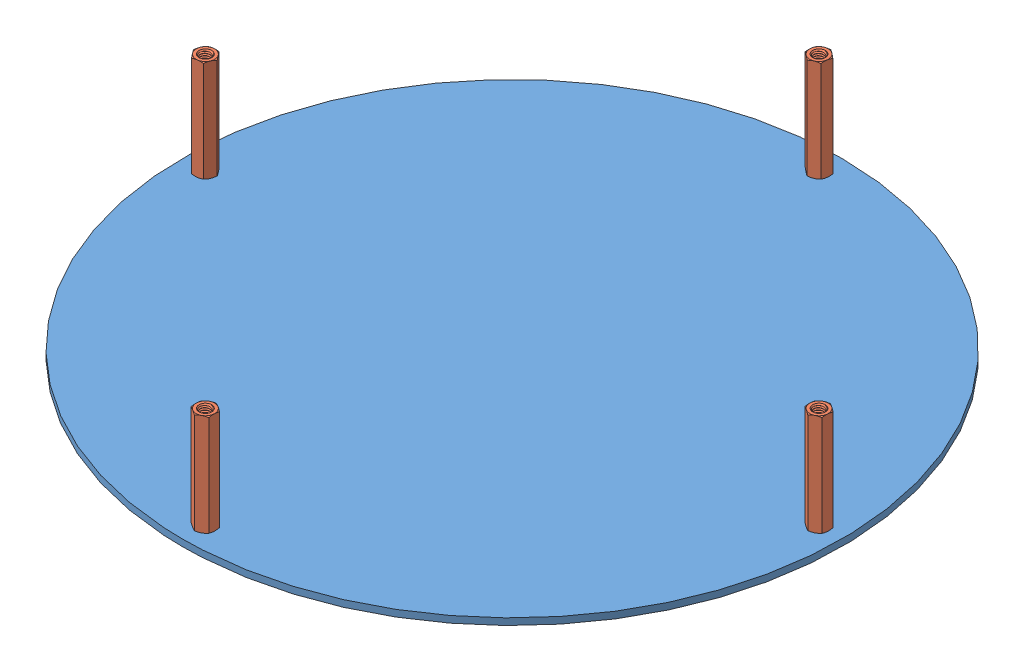
SolidWorks assembly Board_withSpacers, configuration Default. Lengths in mm.
Overall size (162 30.04 162).
5 component instances, 2 part files, 8 mates.
Components (placement in the parent):
- Board-1: Board [Default] at (42.3109 75.7388 139.3539) size (162 1.64 162)
- 98952A120_ALUM MALE-FEM THRDED HEX STANDOFF-1: 98952A120_ALUM MALE-FEM THRDED HEX STANDOFF [98952A120] at (-33.0641 87.5288 139.3539) x (0 -1 0) z (0.922712 0 0.38549) size (30.04 5.2 4.5)
- 98952A120_ALUM MALE-FEM THRDED HEX STANDOFF-2: 98952A120_ALUM MALE-FEM THRDED HEX STANDOFF [98952A120] at (42.3109 87.5288 63.9789) x (0 -1 0) z (0.990608 0 0.136735) size (30.04 5.2 4.5)
- 98952A120_ALUM MALE-FEM THRDED HEX STANDOFF-3: 98952A120_ALUM MALE-FEM THRDED HEX STANDOFF [98952A120] at (42.3109 87.5288 214.7289) x (0 -1 0) z (0.99934 0 0.036314) size (30.04 5.2 4.5)
- 98952A120_ALUM MALE-FEM THRDED HEX STANDOFF-4: 98952A120_ALUM MALE-FEM THRDED HEX STANDOFF [98952A120] at (117.6859 87.5288 139.3539) x (0 -1 0) z (0.997947 0 0.064052) size (30.04 5.2 4.5)
Mates (geometry in assembly coordinates):
- Coincident1: coincident anti-aligned: plane of Board-1 through (42.3109 77.3788 139.3539) normal (0 1 0); plane of 98952A120_ALUM MALE-FEM THRDED HEX STANDOFF-1 through (-32.0625 77.3788 136.9566) normal (0 -1 0)
- Coincident2: coincident anti-aligned: plane of Board-1 through (42.3109 77.3788 139.3539) normal (0 1 0); plane of 98952A120_ALUM MALE-FEM THRDED HEX STANDOFF-3 through (42.4053 77.3788 212.1326) normal (0 -1 0)
- Coincident3: coincident anti-aligned: plane of Board-1 through (42.3109 77.3788 139.3539) normal (0 1 0); plane of 98952A120_ALUM MALE-FEM THRDED HEX STANDOFF-4 through (117.8523 77.3788 136.7612) normal (0 -1 0)
- Coincident4: coincident anti-aligned: plane of Board-1 through (42.3109 77.3788 139.3539) normal (0 1 0); plane of 98952A120_ALUM MALE-FEM THRDED HEX STANDOFF-2 through (42.6662 77.3788 61.4052) normal (0 -1 0)
- Concentric1: concentric anti-aligned: circle of Board-1; circle of 98952A120_ALUM MALE-FEM THRDED HEX STANDOFF-2
- Concentric2: concentric anti-aligned: circle of Board-1; circle of 98952A120_ALUM MALE-FEM THRDED HEX STANDOFF-4
- Concentric3: concentric anti-aligned: circle of Board-1; circle of 98952A120_ALUM MALE-FEM THRDED HEX STANDOFF-1
- Concentric4: concentric anti-aligned: circle of Board-1; circle of 98952A120_ALUM MALE-FEM THRDED HEX STANDOFF-3
